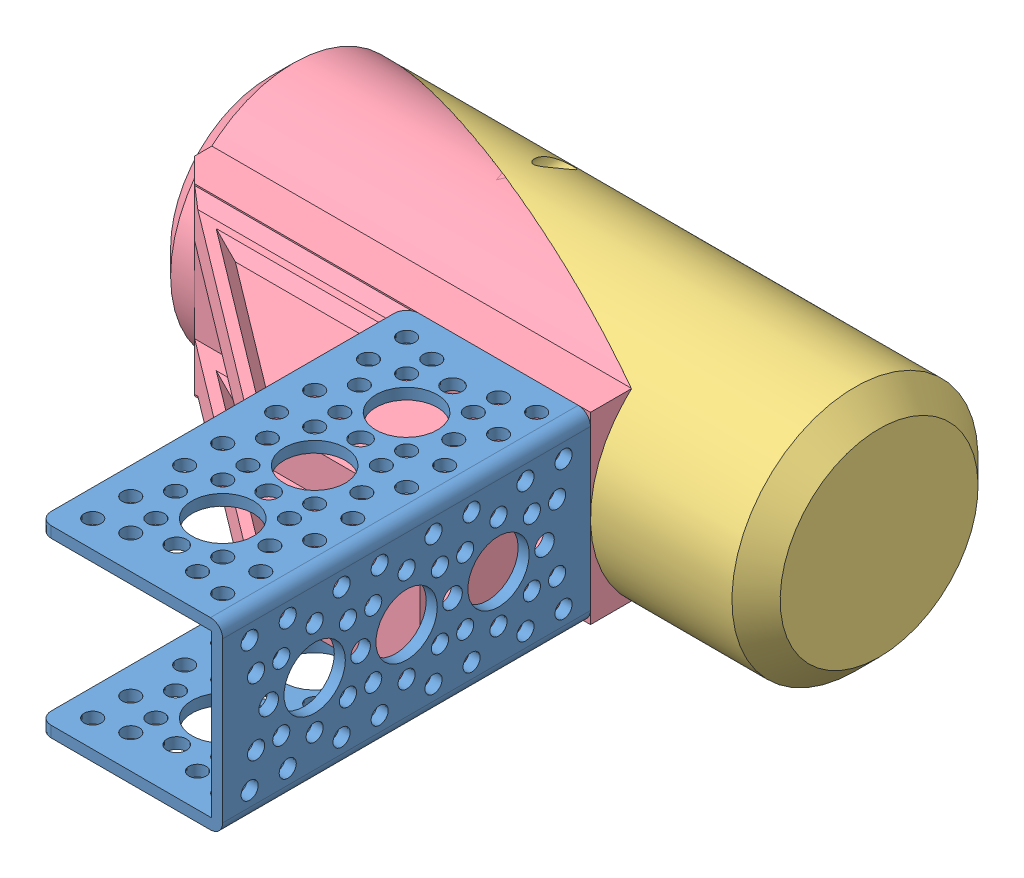
SolidWorks assembly Drive_motor_Assem, configuration Default. Lengths in mm.
Overall size (135.54 51 127.2).
5 component instances, 4 part files, 6 mates.
Components (placement in the parent):
- 3 Aluminum Channel-1: 3 Aluminum Channel [Default] at (13.1106 -33.6837 50.801) x (0 1 0) z (0 0 1) size (38.1 38.1 76.2)
- 638270_Planetary-Motor-1: 638270_Planetary-Motor [Default] at (-68.8894 -14.6337 25.301) x (0 -1 0) z (-1 0 0) size (37 36.95 124.32)
- drive_motor_mount-1: drive_motor_mount [Default] at (45.3927 -125.4448 24.4673) x (0 -1 0) z (-1 0 0) size (51 84 126.3)
  - drive_motor_cap-1: drive_motor_cap [Default] at (-110.811 0.8337 -2.0179) size (51 51 116.5)
  - drive_motor_mount_v2-1: drive_motor_mount_v2 [Default] at (-110.811 0.8337 124.2821) x (-1 0 0) z (0 0 -1) size (51 84 92)
Mates (geometry in assembly coordinates):
- Concentric5: concentric anti-aligned: cylinder of 3 Aluminum Channel-1 through (13.1106 -14.6337 60.326) axis (1 0 0) radius 2.032; cone of drive_motor_mount-1/drive_motor_mount_v2-1 through (10.8246 -14.6337 60.326) axis (-1 0 0)
- Coincident2: coincident anti-aligned: plane of 3 Aluminum Channel-1 through (10.8246 -31.3977 127.001) normal (-1 0 0); plane of drive_motor_mount-1/drive_motor_mount_v2-1 through (10.8246 -5.8837 50.801) normal (1 0 0)
- Concentric6: concentric aligned: cylinder of 3 Aluminum Channel-1 through (-5.9394 4.4163 60.326) axis (0 1 0) radius 2.032; cone of drive_motor_mount-1/drive_motor_mount_v2-1 through (-5.9394 -31.3837 60.326) axis (0 1 0)
- Concentric15: concentric anti-aligned: cylinder of 638270_Planetary-Motor-1 through (-76.2334 -14.6337 25.301) axis (-1 0 0) radius 3; cylinder of drive_motor_mount-1/drive_motor_mount_v2-1 through (-125.8894 -14.6337 25.301) axis (1 0 0) radius 9.98
- Parallel6: parallel anti-aligned: plane of 638270_Planetary-Motor-1 through (-68.8894 -5.6187 25.301) normal (0 1 0); plane of drive_motor_mount-1/drive_motor_mount_v2-1 through (-125.8894 -5.4737 25.301) normal (0 -1 0)
- Coincident7: coincident anti-aligned: plane of 638270_Planetary-Motor-1 through (-68.8894 -14.6337 25.301) normal (-1 0 0); plane of drive_motor_mount-1/drive_motor_mount_v2-1 through (-68.8894 -14.6337 25.301) normal (1 0 0)
